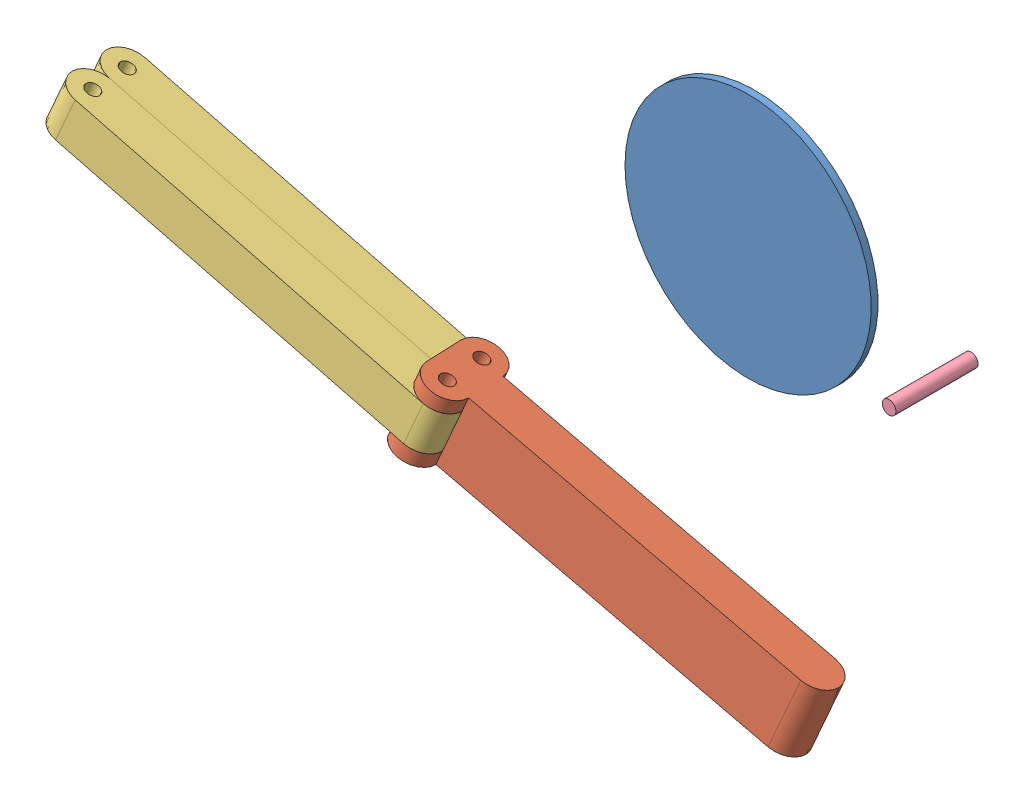
SolidWorks assembly Assem1, configuration Default. Lengths in mm.
Overall size (328.35 183.81 146.7).
5 component instances, 4 part files, 5 mates.
Components (placement in the parent):
- Base Plate-4: Base Plate [Default] at origin size (114.3 114.3 3.17)
- Rough one-1: Rough one [Default] at (-50.9671 -38.1739 75.8164) x (0.933802 -0.343689 -0.09946) z (-0.327249 -0.932809 0.150912) size (177.8 38.1 31.75)
- Parallel Arm-1: Parallel Arm [Default] at (-130.8407 -32.6833 104.8604) x (0.936276 -0.341662 -0.08157) z (0.12765 0.114602 0.985176) size (177.8 19.05 19.05)
- Pin-1: Pin [Default] at (75.18 -26.3191 -25.2063) size (6.35 6.35 38.1)
- Parallel Arm-2: Parallel Arm [Default] at (-133.5962 -34.7478 86.1242) x (0.936276 -0.341662 -0.08157) z (0.12765 0.114602 0.985176) size (177.8 19.05 19.05)
Mates (geometry in assembly coordinates):
- Concentric1: concentric: cylinder of Rough one-1 through (-58.6018 -65.7261 99.3441) axis (0.327249 0.932809 -0.150912) radius 3.175; cylinder of Parallel Arm-1 through (-50.2897 -42.0327 95.5109) axis (-0.327249 -0.932809 0.150912) radius 3.175
- Coincident1: coincident: plane of Rough one-1 through (-50.3848 -65.1409 78.7022) normal (0.327249 0.932809 -0.150912); plane of Parallel Arm-1 through (-205.1576 -5.5638 111.335) normal (-0.327249 -0.932809 0.150912)
- Concentric2: concentric: cylinder of Rough one-1 through (-61.3573 -67.7906 80.6078) axis (0.327249 0.932809 -0.150912) radius 3.175; cylinder of Parallel Arm-2 through (-53.0451 -44.0972 76.7747) axis (-0.327249 -0.932809 0.150912) radius 3.175
- Coincident2: coincident: plane of Rough one-1 through (-50.3848 -65.1409 78.7022) normal (0.327249 0.932809 -0.150912); plane of Parallel Arm-2 through (-207.9131 -7.6283 92.5988) normal (-0.327249 -0.932809 0.150912)
- Parallel1: parallel: plane of Parallel Arm-1 through (-200.1394 11.1146 99.0764) normal (-0.12765 -0.114602 -0.985176); plane of Parallel Arm-2 through (-200.4631 11.2333 99.1077) normal (0.12765 0.114602 0.985176)
